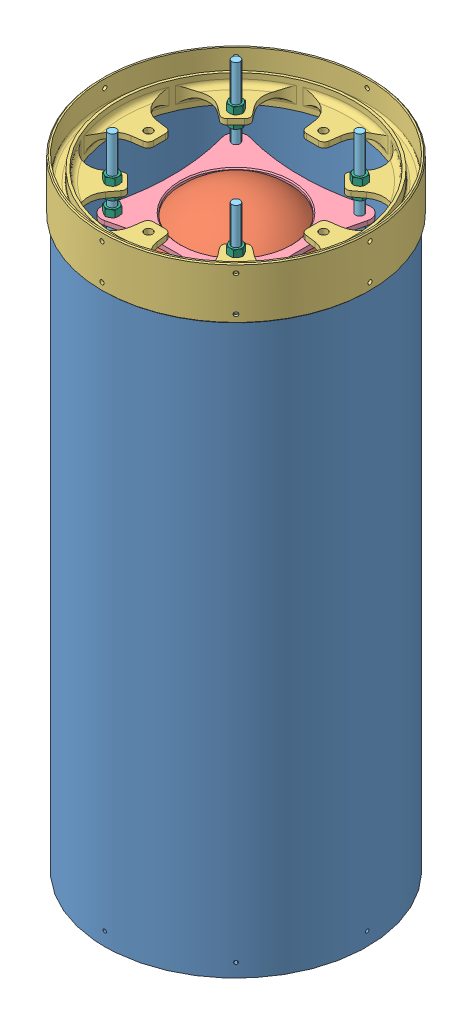
SolidWorks assembly inert_gas_assm, configuration Default. Lengths in mm.
Overall size (323.29 744.54 323.29).
32 component instances, 13 part files, 42 mates.
Components (placement in the parent):
- inert_gas_section-1: inert_gas_section [Default] at (51.0551 -12.216 653.0339) size (304.8 685.8 304.8)
- AIRTANKSFORSALE_GREAT_WHITE-1: AIRTANKSFORSALE_GREAT_WHITE [Default] at (51.0551 673.164 653.0339) x (0.983515 0 -0.180827) z (-0.180827 0 -0.983515) size (175.26 546.1 175.26)
- 000131-R01_RECOVERY_BULKHEAD-1: 000131-R01_RECOVERY_BULKHEAD [Default] at (51.0551 678.3465 653.0339) size (304.8 60.32 304.8)
- inert_gas_holder_thing-1: inert_gas_holder_thing [Default] at (51.0551 163.1564 653.0339) x (-0.707107 0 -0.707107) z (0.707107 0 -0.707107) size (228.6 5.08 228.6)
- inert_gas_holder_thing-2: inert_gas_holder_thing [Default] at (51.0551 644.6915 653.0339) x (0.707107 0 0.707107) z (-0.707107 0 0.707107) size (228.6 5.08 228.6)
- MCMASTER_94435A523-12: MCMASTER_94435A523 [Default] at (-20.7869 122.7215 724.8759) x (0 1 0) z (0.957954 0 -0.286923) size (609.6 9.53 9.53)
- MCMASTER_90670A031_ALUMINUM HEX NUT-1: MCMASTER_90670A031_ALUMINUM HEX NUT [90670A031] at (-20.7869 671.0043 724.8759) x (1 0 0) z (0 -1 0) size (14.29 16.5 9.57)
- MCMASTER_90670A031_ALUMINUM HEX NUT-2: MCMASTER_90670A031_ALUMINUM HEX NUT [90670A031] at (-20.7869 685.6887 724.8759) x (1 0 0) z (0 1 0) size (14.29 16.5 9.57)
- MCMASTER_90670A031_ALUMINUM HEX NUT-3: MCMASTER_90670A031_ALUMINUM HEX NUT [90670A031] at (-20.7869 653.9387 724.8759) x (1 0 0) z (0 1 0) size (14.29 16.5 9.57)
- MCMASTER_90670A031_ALUMINUM HEX NUT-4: MCMASTER_90670A031_ALUMINUM HEX NUT [90670A031] at (-20.7869 158.9892 724.8759) x (0.633683 0 -0.773593) z (0 1 0) size (14.29 16.5 9.57)
- MCMASTER_90670A031_ALUMINUM HEX NUT-5: MCMASTER_90670A031_ALUMINUM HEX NUT [90670A031] at (122.8972 158.9892 724.8759) x (-0.773593 0 -0.633683) z (0 1 0) size (14.29 16.5 9.57)
- MCMASTER_90670A031_ALUMINUM HEX NUT-6: MCMASTER_90670A031_ALUMINUM HEX NUT [90670A031] at (122.8972 158.9892 581.1918) x (-0.633683 0 0.773593) z (0 1 0) size (14.29 16.5 9.57)
- MCMASTER_90670A031_ALUMINUM HEX NUT-7: MCMASTER_90670A031_ALUMINUM HEX NUT [90670A031] at (-20.7869 158.9892 581.1918) x (0.773593 0 0.633683) z (0 1 0) size (14.29 16.5 9.57)
- MCMASTER_90670A031_ALUMINUM HEX NUT-8: MCMASTER_90670A031_ALUMINUM HEX NUT [90670A031] at (122.8972 685.6887 724.8759) x (0 0 -1) z (0 1 0) size (14.29 16.5 9.57)
- MCMASTER_90670A031_ALUMINUM HEX NUT-9: MCMASTER_90670A031_ALUMINUM HEX NUT [90670A031] at (122.8972 685.6887 581.1918) x (-1 0 0) z (0 1 0) size (14.29 16.5 9.57)
- MCMASTER_90670A031_ALUMINUM HEX NUT-10: MCMASTER_90670A031_ALUMINUM HEX NUT [90670A031] at (-20.7869 685.6887 581.1918) x (0 0 1) z (0 1 0) size (14.29 16.5 9.57)
- MCMASTER_90670A031_ALUMINUM HEX NUT-11: MCMASTER_90670A031_ALUMINUM HEX NUT [90670A031] at (122.8972 671.0043 724.8759) x (0 0 -1) z (0 -1 0) size (14.29 16.5 9.57)
- MCMASTER_90670A031_ALUMINUM HEX NUT-12: MCMASTER_90670A031_ALUMINUM HEX NUT [90670A031] at (122.8972 671.0043 581.1918) x (-1 0 0) z (0 -1 0) size (14.29 16.5 9.57)
- MCMASTER_90670A031_ALUMINUM HEX NUT-13: MCMASTER_90670A031_ALUMINUM HEX NUT [90670A031] at (-20.7869 671.0043 581.1918) x (0 0 1) z (0 -1 0) size (14.29 16.5 9.57)
- MCMASTER_94435A523-13: MCMASTER_94435A523 [Default] at (122.8972 122.7215 724.8759) x (0 1 0) z (-0.286923 0 -0.957954) size (609.6 9.53 9.53)
- MCMASTER_94435A523-14: MCMASTER_94435A523 [Default] at (122.8972 122.7215 581.1918) x (0 1 0) z (-0.957954 0 0.286923) size (609.6 9.53 9.53)
- MCMASTER_94435A523-15: MCMASTER_94435A523 [Default] at (-20.7869 122.7215 581.1918) x (0 1 0) z (0.286923 0 0.957954) size (609.6 9.53 9.53)
- KPF1LWA8C8P30000_3D-1: KPF1LWA8C8P30000_3D [Default] at (-44.6859 91.7539 697.7919) x (-0.943171 0 -0.332308) z (0.332308 0 -0.943171) size (80 80 124.46)
- RV2MF-8N-S316-1: RV2MF-8N-S316 [Default] at (77.4519 91.7539 578.1134) x (0.332308 0 -0.943171) z (0 -1 0) size (53.07 103.88 27.09)
  - RV1-MF-8N-BODY-1: RV1-MF-8N-BODY [Default] at origin size (53.07 103.88 27.09)
- 51205K175_EXTREME-PRESSURE 316 SS THREADED PIPE FITTING-1: 51205K175_EXTREME-PRESSURE 316 SS THREADED PIPE FITTING [51205K175] at (51.0551 91.7539 653.0339) x (0.332308 0 -0.943171) z (0.943171 0 0.332308) size (63.86 63.86 31.16)
- 4548K173_STD-WALL TYPE 316-316L SS THRD PIPE NIPPLE-2: 4548K173_STD-WALL TYPE 316-316L SS THRD PIPE NIPPLE [4548K173] at (63.1307 91.7539 618.7606) x (0.332308 0 -0.943171) z (0.942905 -0.023727 0.332215) size (50.97 22.35 22.37)
- 51205K115_EXTREME-PRESSURE 316 SS THREADED PIPE FITTING-1: 51205K115_EXTREME-PRESSURE 316 SS THREADED PIPE FITTING [51205K115] at (51.0551 42.9859 653.0339) x (0.825025 0 0.565096) z (-0.565096 0 0.825025) size (50.93 50.93 23.11)
- KPF1LWA8C8P30000_3D-2: KPF1LWA8C8P30000_3D [Default] at (80.0807 43.0008 702.6108) x (0.825025 0 0.565096) z (0.565096 -0.000611 -0.825025) size (80 80 124.46)
- 48805K195_PRECISION EXTREME-PRESSURE 316SS PIPE FITTING-1: 48805K195_PRECISION EXTREME-PRESSURE 316SS PIPE FITTING [48805K195] at (34.5959 91.7539 699.7491) x (-0.332308 0 0.943171) z (0 1 0) size (53.03 63.43 31.16)
- 4548K173_STD-WALL TYPE 316-316L SS THRD PIPE NIPPLE-3: 4548K173_STD-WALL TYPE 316-316L SS THRD PIPE NIPPLE [4548K173] at (0.3227 91.7539 687.6736) x (-0.943171 0 -0.332308) z (0.332215 -0.023727 -0.942905) size (50.97 22.35 22.37)
- TE_M5200-1: TE_M5200 [Default] at (58.0733 91.7539 708.0209) x (0.14352 -0.901928 -0.407344) z (-0.299718 -0.431887 0.850672) size (25.4 54.61 25.4)
Mates (geometry in assembly coordinates):
- Concentric17: concentric anti-aligned: cylinder of inert_gas_section-1 through (51.0551 673.584 653.0339) axis (0 -1 0) radius 152.4; cylinder of AIRTANKSFORSALE_GREAT_WHITE-1 through (51.0551 139.764 653.0339) axis (0 1 0) radius 87.63
- Concentric22: concentric anti-aligned: cylinder of inert_gas_section-1 through (51.0551 673.584 653.0339) axis (0 -1 0) radius 152.4; cylinder of 000131-R01_RECOVERY_BULKHEAD-1 through (51.0551 722.8129 653.0339) axis (0 1 0) radius 155.575
- Concentric23: concentric aligned: cylinder of inert_gas_section-1 through (-101.3449 657.709 653.0339) axis (-1 0 0) radius 2.0193; cylinder of 000131-R01_RECOVERY_BULKHEAD-1 through (-104.5199 657.709 653.0339) axis (-1 0 0) radius 2.4574
- Distance3: distance = 25.4 mm anti-aligned: plane of inert_gas_holder_thing-2 through (51.0551 649.7715 653.0339) normal (0 1 0); plane of 000131-R01_RECOVERY_BULKHEAD-1 through (51.0551 675.1715 653.0339) normal (0 -1 0)
- Tangent7: tangent aligned: sphere of AIRTANKSFORSALE_GREAT_WHITE-1; cone of inert_gas_holder_thing-1 through (51.0551 166.9664 653.0339) axis (0 -1 0)
- Tangent8: tangent aligned: sphere of AIRTANKSFORSALE_GREAT_WHITE-1; cone of inert_gas_holder_thing-2 through (51.0551 644.6915 653.0339) axis (0 1 0)
- Distance4: distance = 50.8 mm aligned: plane of MCMASTER_94435A523-12 through (-20.7869 732.3215 724.8759) normal (0 1 0); plane of 000131-R01_RECOVERY_BULKHEAD-1 through (51.0551 681.5215 653.0339) normal (0 1 0)
- Concentric25: concentric anti-aligned: cylinder of MCMASTER_94435A523-12 through (-20.7869 732.3215 724.8759) axis (0 -1 0) radius 4.7625; circle of MCMASTER_90670A031_ALUMINUM HEX NUT-4
- Coincident9: coincident anti-aligned: plane of inert_gas_holder_thing-2 through (51.0551 649.7715 653.0339) normal (0 1 0); plane of MCMASTER_90670A031_ALUMINUM HEX NUT-3 through (-27.9307 649.7715 720.7515) normal (0 -1 0)
- Coincident10: coincident anti-aligned: plane of 000131-R01_RECOVERY_BULKHEAD-1 through (51.0551 681.5215 653.0339) normal (0 1 0); plane of MCMASTER_90670A031_ALUMINUM HEX NUT-2 through (-27.9307 681.5215 720.7515) normal (0 -1 0)
- Coincident11: coincident anti-aligned: plane of 000131-R01_RECOVERY_BULKHEAD-1 through (51.0551 675.1715 653.0339) normal (0 -1 0); plane of MCMASTER_90670A031_ALUMINUM HEX NUT-1 through (-27.9307 675.1715 729.0004) normal (0 1 0)
- Concentric24: concentric anti-aligned: cylinder of MCMASTER_94435A523-12 through (-20.7869 732.3215 724.8759) axis (0 -1 0) radius 4.7625; circle of MCMASTER_90670A031_ALUMINUM HEX NUT-3
- Coincident13: coincident anti-aligned: cylinder of MCMASTER_94435A523-12 through (-20.7869 732.3215 724.8759) axis (0 -1 0) radius 4.7625; circle of MCMASTER_90670A031_ALUMINUM HEX NUT-2
- Coincident14: coincident aligned: cylinder of MCMASTER_94435A523-12 through (-20.7869 732.3215 724.8759) axis (0 -1 0) radius 4.7625; circle of MCMASTER_90670A031_ALUMINUM HEX NUT-1
- Coincident15: coincident anti-aligned: plane of inert_gas_holder_thing-1 through (51.0551 163.1564 653.0339) normal (0 -1 0); plane of MCMASTER_90670A031_ALUMINUM HEX NUT-4 through (-28.5044 163.1564 727.7887) normal (0 1 0)
- Concentric26: concentric aligned: cylinder of 000131-R01_RECOVERY_BULKHEAD-1 through (-20.7869 681.5215 724.8759) axis (0 1 0) radius 4.7625; cylinder of inert_gas_holder_thing-2 through (-20.7869 649.7715 724.8759) axis (0 1 0) radius 4.7625
- Concentric27: concentric aligned: cylinder of 000131-R01_RECOVERY_BULKHEAD-1 through (-20.7869 681.5215 581.1918) axis (0 1 0) radius 4.7625; cylinder of inert_gas_holder_thing-2 through (-20.7869 649.7715 581.1918) axis (0 1 0) radius 4.7625
- Concentric28: concentric anti-aligned: cylinder of 000131-R01_RECOVERY_BULKHEAD-1 through (-20.7869 681.5215 724.8759) axis (0 1 0) radius 4.7625; cylinder of MCMASTER_94435A523-12 through (-20.7869 732.3215 724.8759) axis (0 -1 0) radius 4.7625
- Concentric29: concentric aligned: cylinder of AIRTANKSFORSALE_GREAT_WHITE-1 through (51.0551 500673.164 653.0339) axis (0 -1 0) radius 9.525; cylinder of 51205K175_EXTREME-PRESSURE 316 SS THREADED PIPE FITTING-1 through (51.0551 122.9959 653.0339) axis (0 -1 0) radius 15.5812
- Concentric30: concentric anti-aligned: cylinder of inert_gas_holder_thing-1 through (-20.7869 168.2364 581.1918) axis (0 1 0) radius 4.7625; cylinder of MCMASTER_94435A523-15 through (-20.7869 732.3215 581.1918) axis (0 -1 0) radius 4.7625
- Concentric31: concentric anti-aligned: cylinder of inert_gas_holder_thing-1 through (-20.7869 168.2364 724.8759) axis (0 1 0) radius 4.7625; cylinder of MCMASTER_94435A523-12 through (-20.7869 732.3215 724.8759) axis (0 -1 0) radius 4.7625
- Concentric43: concentric anti-aligned: cylinder of 51205K175_EXTREME-PRESSURE 316 SS THREADED PIPE FITTING-1 through (61.4371 91.7539 623.5673) axis (-0.332308 0 0.943171) radius 15.5812; cylinder of 4548K173_STD-WALL TYPE 316-316L SS THRD PIPE NIPPLE-2 through (63.1307 91.7539 618.7606) axis (0.332308 0 -0.943171) radius 10.668
- Concentric45: concentric anti-aligned: cylinder of RV2MF-8N-S316-1/RV1-MF-8N-BODY-1 through (78.0833 91.7539 576.3214) axis (-0.332308 0 0.943171) radius 8.8011; cylinder of 4548K173_STD-WALL TYPE 316-316L SS THRD PIPE NIPPLE-2 through (63.1307 91.7539 618.7606) axis (0.332308 0 -0.943171) radius 10.668
- Coincident30: coincident anti-aligned: plane of RV2MF-8N-S316-1/RV1-MF-8N-BODY-1 through (64.8242 91.7539 613.9539) normal (-0.332308 0 0.943171); circle of 4548K173_STD-WALL TYPE 316-316L SS THRD PIPE NIPPLE-2
- Coincident31: coincident aligned: plane of 51205K175_EXTREME-PRESSURE 316 SS THREADED PIPE FITTING-1 through (61.4371 91.7539 623.5673) normal (0.332308 0 -0.943171); circle of 4548K173_STD-WALL TYPE 316-316L SS THRD PIPE NIPPLE-2
- Coincident35: coincident anti-aligned: plane of 51205K175_EXTREME-PRESSURE 316 SS THREADED PIPE FITTING-1 through (51.0551 60.5119 653.0339) normal (0 -1 0); plane of 51205K115_EXTREME-PRESSURE 316 SS THREADED PIPE FITTING-1 through (50.0687 60.5119 665.8275) normal (0 1 0)
- Concentric49: concentric anti-aligned: cylinder of 51205K175_EXTREME-PRESSURE 316 SS THREADED PIPE FITTING-1 through (51.0551 73.9739 653.0339) axis (0 1 0) radius 8.001; cylinder of 51205K115_EXTREME-PRESSURE 316 SS THREADED PIPE FITTING-1 through (51.0551 80.3239 653.0339) axis (0 -1 0) radius 7.8289
- Concentric50: concentric anti-aligned: cylinder of 51205K115_EXTREME-PRESSURE 316 SS THREADED PIPE FITTING-1 through (81.8599 42.9859 674.1334) axis (-0.825025 0 -0.565096) radius 7.8289; cone of KPF1LWA8C8P30000_3D-2 through (67.0338 42.9859 663.9784) axis (0.825025 0 0.565096)
- Angle1: planar angle = 1.308997 rad anti-aligned: plane of 51205K115_EXTREME-PRESSURE 316 SS THREADED PIPE FITTING-1 through (64.5645 51.7489 648.8177) normal (0.565096 0 -0.825025); plane of 51205K175_EXTREME-PRESSURE 316 SS THREADED PIPE FITTING-1 through (42.2215 80.0381 637.4998) normal (-0.943171 0 -0.332308)
- Coincident39: coincident: circle of 51205K115_EXTREME-PRESSURE 316 SS THREADED PIPE FITTING-1; cone of KPF1LWA8C8P30000_3D-2 through (65.4527 42.9859 662.8954) axis (0.825025 0 0.565096)
- Parallel6: parallel aligned: plane of RV2MF-8N-S316-1/RV1-MF-8N-BODY-1 through (51.6198 109.3515 609.3016) normal (-0.943171 0 -0.332308); plane of 51205K175_EXTREME-PRESSURE 316 SS THREADED PIPE FITTING-1 through (42.2215 80.0381 637.4998) normal (-0.943171 0 -0.332308)
- Concentric51: concentric anti-aligned: cylinder of 51205K175_EXTREME-PRESSURE 316 SS THREADED PIPE FITTING-1 through (56.9636 91.7539 636.2643) axis (-0.332308 0 0.943171) radius 8.001; cylinder of 48805K195_PRECISION EXTREME-PRESSURE 316SS PIPE FITTING-1 through (34.5959 91.7539 699.7491) axis (0.332308 0 -0.943171) radius 6.35
- Angle2: planar angle = 1.570796 rad aligned: plane of 48805K195_PRECISION EXTREME-PRESSURE 316SS PIPE FITTING-1 through (34.5959 105.2476 699.7491) normal (0 1 0); plane of 51205K175_EXTREME-PRESSURE 316 SS THREADED PIPE FITTING-1 through (42.2215 80.0381 637.4998) normal (-0.943171 0 -0.332308)
- Concentric52: concentric aligned: cone of KPF1LWA8C8P30000_3D-1 through (-5.8017 91.7539 685.5158) axis (-0.943171 0 -0.332308); cylinder of 48805K195_PRECISION EXTREME-PRESSURE 316SS PIPE FITTING-1 through (55.2697 91.7539 707.0331) axis (-0.943171 0 -0.332308) radius 6.35
- Coincident41: coincident anti-aligned: plane of 51205K175_EXTREME-PRESSURE 316 SS THREADED PIPE FITTING-1 through (40.6732 91.7539 682.5004) normal (-0.332308 0 0.943171); plane of 48805K195_PRECISION EXTREME-PRESSURE 316SS PIPE FITTING-1 through (40.6732 118.7414 682.5004) normal (0.332308 0 -0.943171)
- Concentric53: concentric aligned: cone of KPF1LWA8C8P30000_3D-1 through (-5.8017 91.7539 685.5158) axis (-0.943171 0 -0.332308); cylinder of 4548K173_STD-WALL TYPE 316-316L SS THRD PIPE NIPPLE-3 through (0.3227 91.7539 687.6736) axis (-0.943171 0 -0.332308) radius 10.668
- Concentric54: concentric aligned: cylinder of 48805K195_PRECISION EXTREME-PRESSURE 316SS PIPE FITTING-1 through (55.2697 91.7539 707.0331) axis (-0.943171 0 -0.332308) radius 6.35; cylinder of 4548K173_STD-WALL TYPE 316-316L SS THRD PIPE NIPPLE-3 through (0.3227 91.7539 687.6736) axis (-0.943171 0 -0.332308) radius 10.668
- Coincident42: coincident: cone of KPF1LWA8C8P30000_3D-1 through (-3.9941 91.7539 686.1527) axis (-0.943171 0 -0.332308); circle of 4548K173_STD-WALL TYPE 316-316L SS THRD PIPE NIPPLE-3
- Coincident43: coincident aligned: plane of 48805K195_PRECISION EXTREME-PRESSURE 316SS PIPE FITTING-1 through (5.1294 91.7539 689.3672) normal (-0.943171 0 -0.332308); circle of 4548K173_STD-WALL TYPE 316-316L SS THRD PIPE NIPPLE-3
- Concentric55: concentric aligned: cylinder of 48805K195_PRECISION EXTREME-PRESSURE 316SS PIPE FITTING-1 through (55.2697 91.7539 707.0331) axis (-0.943171 0 -0.332308) radius 6.35; cylinder of TE_M5200-1 through (58.0733 91.7539 708.0209) axis (-0.943171 0 -0.332308) radius 8.89
- Distance5: distance = 2.54 mm anti-aligned: plane of TE_M5200-1 through (68.2808 80.2994 705.8019) normal (-0.943171 0 -0.332308); plane of 48805K195_PRECISION EXTREME-PRESSURE 316SS PIPE FITTING-1 through (64.0625 91.7539 710.1311) normal (0.943171 0 0.332308)
- Parallel7: parallel aligned: plane of KPF1LWA8C8P30000_3D-1 through (-43.5228 109.2539 694.4908) normal (0 1 0); plane of 48805K195_PRECISION EXTREME-PRESSURE 316SS PIPE FITTING-1 through (34.5959 105.2476 699.7491) normal (0 1 0)
